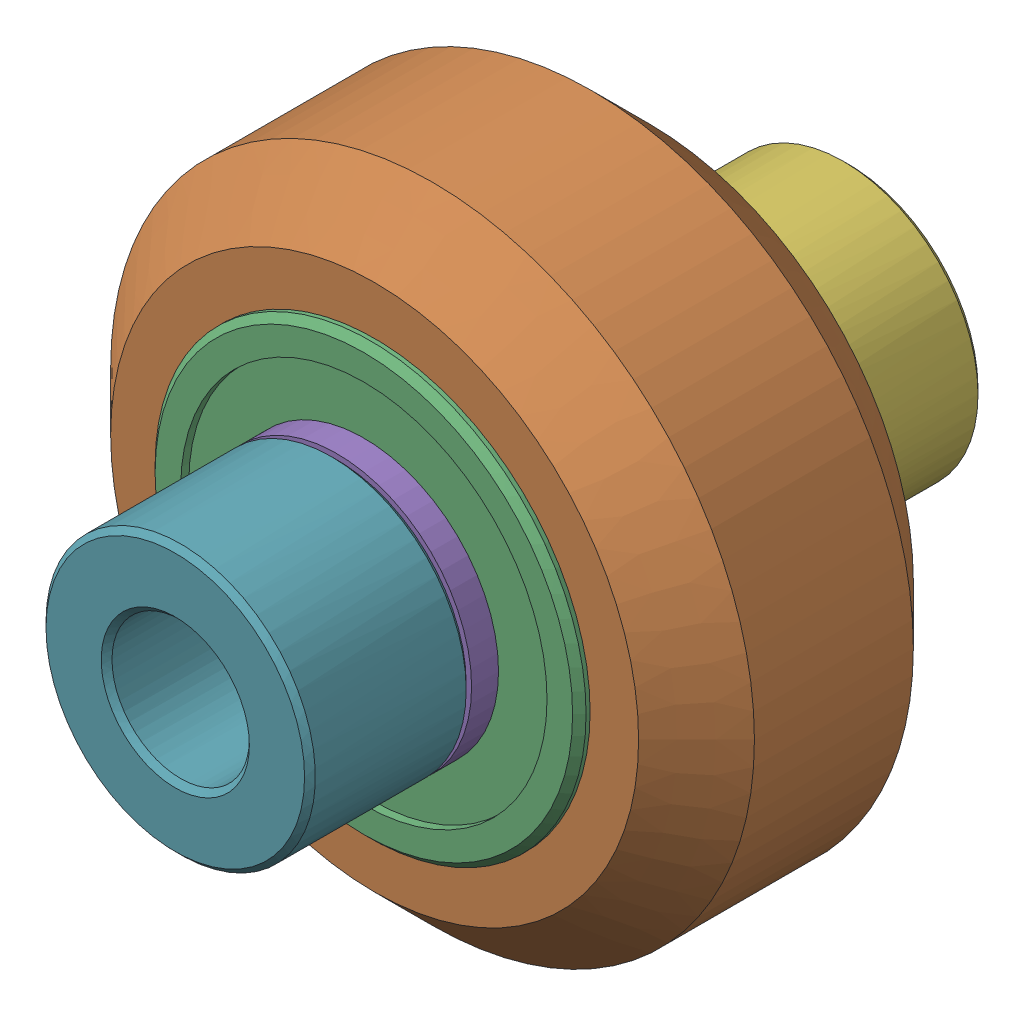
SolidWorks assembly Inboard Wheel Stack, configuration Default. Lengths in mm.
Overall size (23.9 23.9 25).
9 component instances, 4 part files, 0 mates.
Components (placement in the parent):
- Xtreme Solid V Wheel Kit Assembly-1: Xtreme Solid V Wheel Kit Assembly [Default] at origin size (23.9 23.9 13)
  - Precision Shim - 10x5x1mm-1: Precision Shim - 10x5x1mm [Default] at origin size (10 10 1)
  - Xtreme Solid V Wheel Assembly-1: Xtreme Solid V Wheel Assembly [Default] at (45.15 25 -23.5) size (23.9 23.9 11)
    - Xtreme Solid V Wheel-1: Xtreme Solid V Wheel [Default] at (-45.15 -25 30) x (0 0 1) z (-1 0 0) size (10.2 23.9 23.9)
    - Wheel+Kit+-+5x16x5mm+Sealed+Radial+Ball+Bearing.step.f3d-1: Wheel+Kit+-+5x16x5mm+Sealed+Radial+Ball+Bearing.step.f3d [Default] at (-45.15 -25 30) x (0 1 0) z (-1 0 0) size (16 5 16)
    - Wheel+Kit+-+5x16x5mm+Sealed+Radial+Ball+Bearing.step.f3d-2: Wheel+Kit+-+5x16x5mm+Sealed+Radial+Ball+Bearing.step.f3d [Default] at (-45.15 -25 30) x (0 1 0) z (1 0 0) size (16 5 16)
  - Precision Shim - 10x5x1mm-2: Precision Shim - 10x5x1mm [Default] at (0 0 12) size (10 10 1)
- Aluminum Spacer 6mm-1: Aluminum Spacer 6mm [Default] at (0 0 -6) size (10 10 6)
- Aluminum Spacer 6mm-2: Aluminum Spacer 6mm [Default] at (0 0 13) size (10 10 6)
